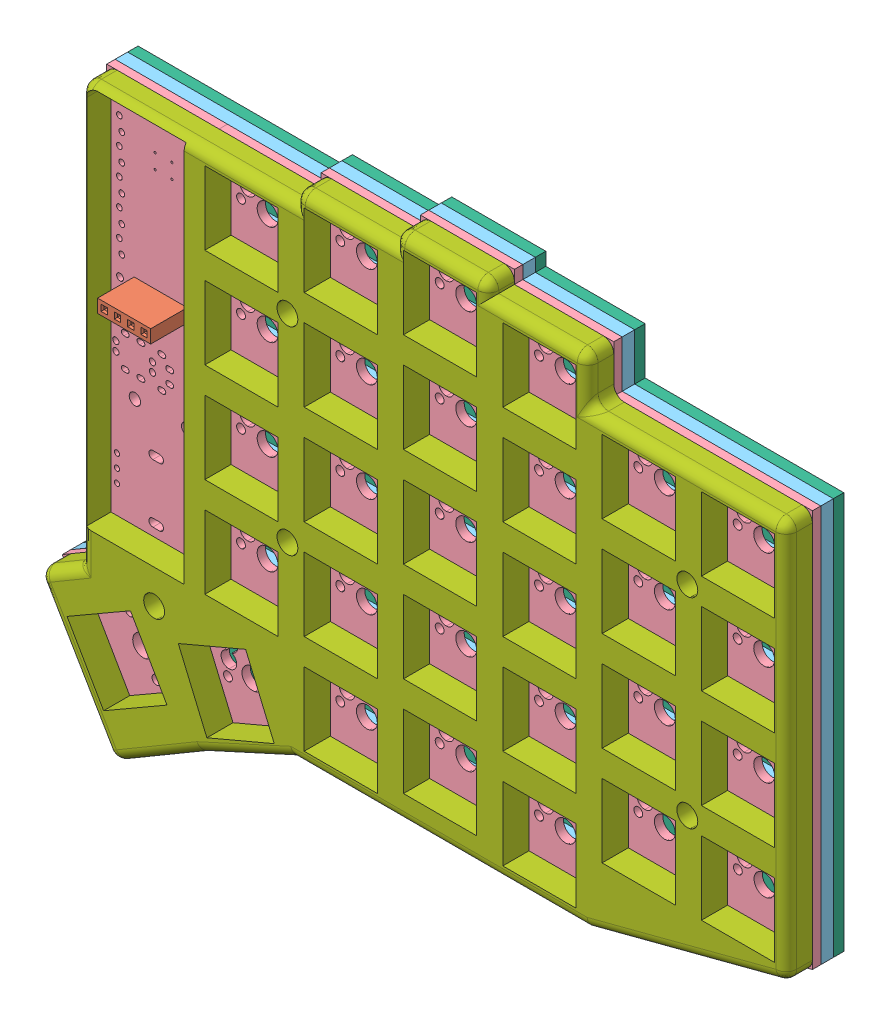
SolidWorks assembly rightHalf, configuration По умолчанию. Lengths in mm.
Overall size (143.5 115.5 13.05).
73 component instances, 7 part files, 6 mates.
Components (placement in the parent):
- SofleKeyboard-1: SofleKeyboard [По умолчанию] at origin size (143.5 115.5 10.1)
  - SofleKeyboard.step-1: SofleKeyboard.step [По умолчанию] at origin size (143.5 115.5 10.1)
    - D_SOD-123.step-1: D_SOD-123.step [По умолчанию] at (24.67 -17.448 -0.05) x (1 0 0) z (0 0 -1) size (3.8 1.6 1.25)
      - D_SOD_123.step-1: D_SOD_123.step [По умолчанию] at origin size (3.8 1.6 1.25)
    - D_SOD-123.step-2: D_SOD-123.step [По умолчанию] at (44.57 -15.148 -0.05) x (1 0 0) z (0 0 -1) size (3.8 1.6 1.25)
      - D_SOD_123.step-1: D_SOD_123.step [По умолчанию] at origin size (3.8 1.6 1.25)
    - D_SOD-123.step-3: D_SOD-123.step [По умолчанию] at (62.67 -12.748 -0.05) x (1 0 0) z (0 0 -1) size (3.8 1.6 1.25)
      - D_SOD_123.step-1: D_SOD_123.step [По умолчанию] at origin size (3.8 1.6 1.25)
    - D_SOD-123.step-4: D_SOD-123.step [По умолчанию] at (81.77 -15.048 -0.05) x (1 0 0) z (0 0 -1) size (3.8 1.6 1.25)
      - D_SOD_123.step-1: D_SOD_123.step [По умолчанию] at origin size (3.8 1.6 1.25)
    - D_SOD-123.step-5: D_SOD-123.step [По умолчанию] at (100.67 -24.248 -0.05) x (1 0 0) z (0 0 -1) size (3.8 1.6 1.25)
      - D_SOD_123.step-1: D_SOD_123.step [По умолчанию] at origin size (3.8 1.6 1.25)
    - D_SOD-123.step-6: D_SOD-123.step [По умолчанию] at (132.17 -24.048 -0.05) x (1 0 0) z (0 0 -1) size (3.8 1.6 1.25)
      - D_SOD_123.step-1: D_SOD_123.step [По умолчанию] at origin size (3.8 1.6 1.25)
    - D_SOD-123.step-7: D_SOD-123.step [По умолчанию] at (24.67 -20.548 -0.05) x (1 0 0) z (0 0 -1) size (3.8 1.6 1.25)
      - D_SOD_123.step-1: D_SOD_123.step [По умолчанию] at origin size (3.8 1.6 1.25)
    - D_SOD-123.step-8: D_SOD-123.step [По умолчанию] at (45.57 -18.148 -0.05) x (1 0 0) z (0 0 -1) size (3.8 1.6 1.25)
      - D_SOD_123.step-1: D_SOD_123.step [По умолчанию] at origin size (3.8 1.6 1.25)
    - D_SOD-123.step-9: D_SOD-123.step [По умолчанию] at (62.77 -15.948 -0.05) x (1 0 0) z (0 0 -1) size (3.8 1.6 1.25)
      - D_SOD_123.step-1: D_SOD_123.step [По умолчанию] at origin size (3.8 1.6 1.25)
    - D_SOD-123.step-10: D_SOD-123.step [По умолчанию] at (81.77 -18.148 -0.05) x (1 0 0) z (0 0 -1) size (3.8 1.6 1.25)
      - D_SOD_123.step-1: D_SOD_123.step [По умолчанию] at origin size (3.8 1.6 1.25)
    - D_SOD-123.step-11: D_SOD-123.step [По умолчанию] at (100.67 -27.148 -0.05) x (1 0 0) z (0 0 -1) size (3.8 1.6 1.25)
      - D_SOD_123.step-1: D_SOD_123.step [По умолчанию] at origin size (3.8 1.6 1.25)
    - D_SOD-123.step-12: D_SOD-123.step [По умолчанию] at (132.17 -27.148 -0.05) x (1 0 0) z (0 0 -1) size (3.8 1.6 1.25)
      - D_SOD_123.step-1: D_SOD_123.step [По умолчанию] at origin size (3.8 1.6 1.25)
    - D_SOD-123.step-13: D_SOD-123.step [По умолчанию] at (24.67 -55.448 -0.05) x (1 0 0) z (0 0 -1) size (3.8 1.6 1.25)
      - D_SOD_123.step-1: D_SOD_123.step [По умолчанию] at origin size (3.8 1.6 1.25)
    - D_SOD-123.step-14: D_SOD-123.step [По умолчанию] at (44.57 -53.248 -0.05) x (1 0 0) z (0 0 -1) size (3.8 1.6 1.25)
      - D_SOD_123.step-1: D_SOD_123.step [По умолчанию] at origin size (3.8 1.6 1.25)
    - D_SOD-123.step-15: D_SOD-123.step [По умолчанию] at (62.77 -50.848 -0.05) x (1 0 0) z (0 0 -1) size (3.8 1.6 1.25)
      - D_SOD_123.step-1: D_SOD_123.step [По умолчанию] at origin size (3.8 1.6 1.25)
    - D_SOD-123.step-16: D_SOD-123.step [По умолчанию] at (81.77 -53.048 -0.05) x (1 0 0) z (0 0 -1) size (3.8 1.6 1.25)
      - D_SOD_123.step-1: D_SOD_123.step [По умолчанию] at origin size (3.8 1.6 1.25)
    - D_SOD-123.step-17: D_SOD-123.step [По умолчанию] at (100.47 -62.248 -0.05) x (1 0 0) z (0 0 -1) size (3.8 1.6 1.25)
      - D_SOD_123.step-1: D_SOD_123.step [По умолчанию] at origin size (3.8 1.6 1.25)
    - D_SOD-123.step-18: D_SOD-123.step [По умолчанию] at (131.87 -62.248 -0.05) x (1 0 0) z (0 0 -1) size (3.8 1.6 1.25)
      - D_SOD_123.step-1: D_SOD_123.step [По умолчанию] at origin size (3.8 1.6 1.25)
    - D_SOD-123.step-19: D_SOD-123.step [По умолчанию] at (24.67 -58.548 -0.05) x (1 0 0) z (0 0 -1) size (3.8 1.6 1.25)
      - D_SOD_123.step-1: D_SOD_123.step [По умолчанию] at origin size (3.8 1.6 1.25)
    - D_SOD-123.step-20: D_SOD-123.step [По умолчанию] at (45.57 -56.248 -0.05) x (1 0 0) z (0 0 -1) size (3.8 1.6 1.25)
      - D_SOD_123.step-1: D_SOD_123.step [По умолчанию] at origin size (3.8 1.6 1.25)
    - D_SOD-123.step-21: D_SOD-123.step [По умолчанию] at (62.77 -53.948 -0.05) x (1 0 0) z (0 0 -1) size (3.8 1.6 1.25)
      - D_SOD_123.step-1: D_SOD_123.step [По умолчанию] at origin size (3.8 1.6 1.25)
    - D_SOD-123.step-22: D_SOD-123.step [По умолчанию] at (81.77 -56.248 -0.05) x (1 0 0) z (0 0 -1) size (3.8 1.6 1.25)
      - D_SOD_123.step-1: D_SOD_123.step [По умолчанию] at origin size (3.8 1.6 1.25)
    - D_SOD-123.step-23: D_SOD-123.step [По умолчанию] at (100.47 -65.448 -0.05) x (1 0 0) z (0 0 -1) size (3.8 1.6 1.25)
      - D_SOD_123.step-1: D_SOD_123.step [По умолчанию] at origin size (3.8 1.6 1.25)
    - D_SOD-123.step-24: D_SOD-123.step [По умолчанию] at (131.97 -65.448 -0.05) x (1 0 0) z (0 0 -1) size (3.8 1.6 1.25)
      - D_SOD_123.step-1: D_SOD_123.step [По умолчанию] at origin size (3.8 1.6 1.25)
    - D_SOD-123.step-25: D_SOD-123.step [По умолчанию] at (16.97 -58.458 -0.05) x (1 0 0) z (0 0 -1) size (3.8 1.6 1.25)
      - D_SOD_123.step-1: D_SOD_123.step [По умолчанию] at origin size (3.8 1.6 1.25)
    - D_SOD-123.step-26: D_SOD-123.step [По умолчанию] at (20.07 -78.748 -0.05) x (0.5 -0.866025 0) z (0 0 -1) size (3.8 1.6 1.25)
      - D_SOD_123.step-1: D_SOD_123.step [По умолчанию] at origin size (3.8 1.6 1.25)
    - D_SOD-123.step-27: D_SOD-123.step [По умолчанию] at (34.17 -77.448 -0.05) x (1 0 0) z (0 0 -1) size (3.8 1.6 1.25)
      - D_SOD_123.step-1: D_SOD_123.step [По умолчанию] at origin size (3.8 1.6 1.25)
    - D_SOD-123.step-28: D_SOD-123.step [По умолчанию] at (53.17 -75.248 -0.05) x (1 0 0) z (0 0 -1) size (3.8 1.6 1.25)
      - D_SOD_123.step-1: D_SOD_123.step [По умолчанию] at origin size (3.8 1.6 1.25)
    - D_SOD-123.step-29: D_SOD-123.step [По умолчанию] at (72.67 -72.258 -0.05) x (1 0 0) z (0 0 -1) size (3.8 1.6 1.25)
      - D_SOD_123.step-1: D_SOD_123.step [По умолчанию] at origin size (3.8 1.6 1.25)
    - PinSocket_1x04_P2.54mm_Vertical.step-1: PinSocket_1x04_P2.54mm_Vertical.step [По умолчанию] at (6.57 -33.858 1.65) x (0 1 0) z (0 0 1) size (2.54 10.16 10.1)
      - PinSocket_1x04_P254mm_Vertical.step-1: PinSocket_1x04_P254mm_Vertical.step [По умолчанию] at origin size (2.54 10.16 10.1)
    - D_SOD-123.step-30: D_SOD-123.step [По умолчанию] at (90.87 -74.758 -0.05) x (1 0 0) z (0 0 -1) size (3.8 1.6 1.25)
      - D_SOD_123.step-1: D_SOD_123.step [По умолчанию] at origin size (3.8 1.6 1.25)
    - R_1206_3216Metric.step-1: R_1206_3216Metric.step [По умолчанию] at (12.47 -11.458 -0.05) x (0 -1 0) z (0 0 -1) size (3.2 1.6 0.55)
      - R_1206_3216Metric-0.step-1: R_1206_3216Metric-0.step [По умолчанию] at origin size (3.2 1.6 0.55)
    - R_1206_3216Metric.step-2: R_1206_3216Metric.step [По умолчанию] at (9.27 -11.458 -0.05) x (0 -1 0) z (0 0 -1) size (3.2 1.6 0.55)
      - R_1206_3216Metric-0.step-1: R_1206_3216Metric-0.step [По умолчанию] at origin size (3.2 1.6 0.55)
    - _autosave-SofleKeyboard_PCB.step-1: _autosave-SofleKeyboard_PCB.step [По умолчанию] at origin size (143.5 115.5 1.6)
- bottomCaseRight-1: bottomCaseRight [По умолчанию] at (0 0 -2.4) x (0 0 1) z (-1 0 0) size (4.4 115.41 143.5)
  - bottom1-1: bottom1 [По умолчанию] at origin size (2.4 115.41 143.5)
  - bottom2-1: bottom2 [По умолчанию] at (-2 0 0) x (0 0 -1) z (0 -1 0) size (143.5 2 115.41)
- topRight-1: topRight [По умолчанию] at (0 0 1.6) x (0 0 1) z (-1 0 0) size (5 114.67 142.76)
Mates (geometry in assembly coordinates):
- Концентричный1: concentric aligned: cylinder of SofleKeyboard-1/SofleKeyboard.step-1/_autosave-SofleKeyboard_PCB.step-1 through (39.57 -19.048 -0.045) axis (0 0 -1) radius 2.05; cylinder of topRight-1 through (39.57 -19.048 6.6) axis (0 0 -1) radius 2
- Концентричный2: concentric aligned: cylinder of SofleKeyboard-1/SofleKeyboard.step-1/_autosave-SofleKeyboard_PCB.step-1 through (39.57 -56.958 -0.045) axis (0 0 -1) radius 2.05; cylinder of topRight-1 through (39.57 -56.958 6.6) axis (0 0 -1) radius 2
- Совпадение3: coincident anti-aligned: plane of SofleKeyboard-1/SofleKeyboard.step-1/_autosave-SofleKeyboard_PCB.step-1 through (0 0 1.6) normal (0 0 1); plane of topRight-1 through (0 0 1.6) normal (0 0 -1)
- Концентричный4: concentric aligned: cylinder of SofleKeyboard-1/SofleKeyboard.step-1/_autosave-SofleKeyboard_PCB.step-1 through (39.57 -19.048 -0.045) axis (0 0 -1) radius 2.05; cylinder of bottomCaseRight-1/bottom1-1 through (39.57 -19.048 0) axis (0 0 -1) radius 1.75
- Концентричный5: concentric aligned: cylinder of SofleKeyboard-1/SofleKeyboard.step-1/_autosave-SofleKeyboard_PCB.step-1 through (39.57 -56.958 -0.045) axis (0 0 -1) radius 2.05; cylinder of bottomCaseRight-1/bottom1-1 through (39.57 -56.958 0) axis (0 0 -1) radius 1.75
- Совпадение4: coincident anti-aligned: plane of SofleKeyboard-1/SofleKeyboard.step-1/_autosave-SofleKeyboard_PCB.step-1 through (0 0 0) normal (0 0 -1); plane of bottomCaseRight-1/bottom1-1 through (0 0 0) normal (0 0 1)
